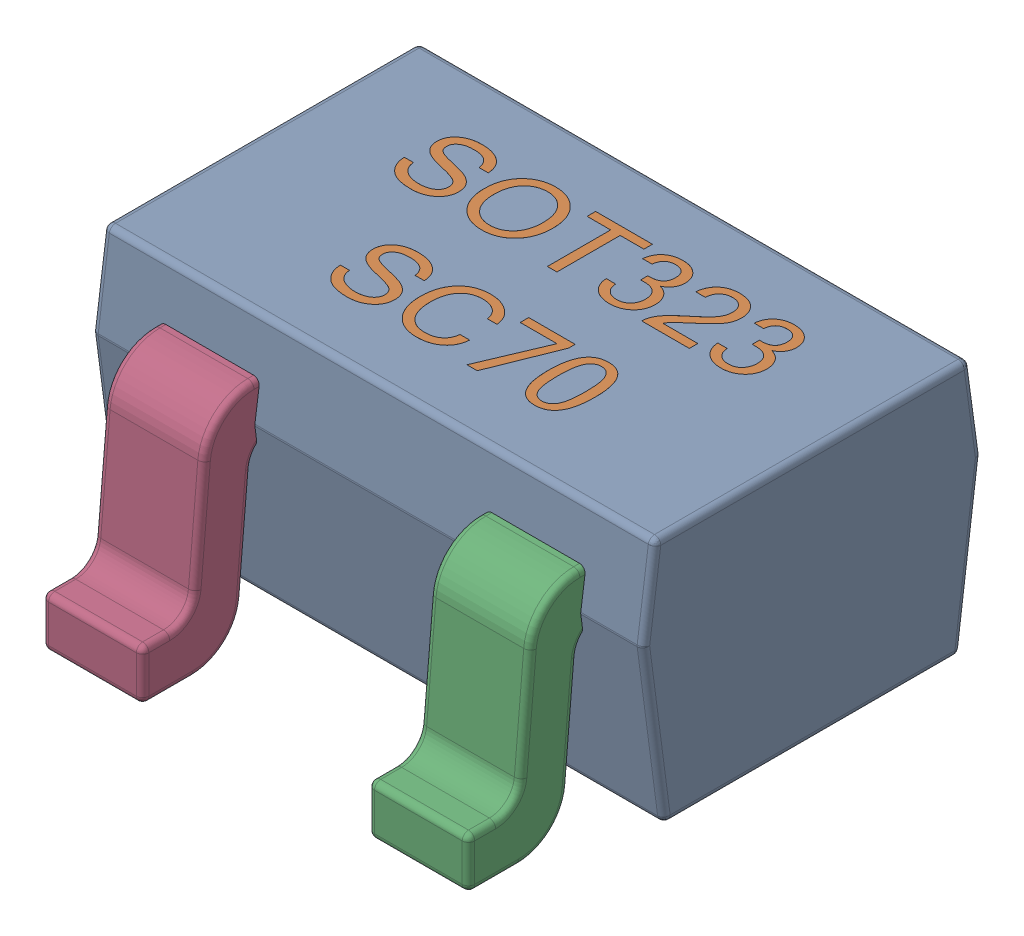
SolidWorks assembly SOT323_(SC70-3)-1.step, configuration Default. Lengths in mm.
Overall size (2.2 1.1 2.25).
5 component instances, 3 part files, 0 mates.
Components (placement in the parent):
- User_Library-SOT323_(SC70-3)-1_K_X_F6rper_1.step-1: User_Library-SOT323_(SC70-3)-1_K_X_F6rper_1.step [Default] x (0 0 -1) z (0 1 0) size (1.35 2.2 1)
- User_Library-SOT323_(SC70-3)-1_Beschriftung_1.step-1: User_Library-SOT323_(SC70-3)-1_Beschriftung_1.step [Default] x (0 0 -1) z (0 1 0) size (0.8 1.45 0.06)
- User_Library-SOT323_(SC70-3)-1_Pins_1.step-1: User_Library-SOT323_(SC70-3)-1_Pins_1.step [Default] at (0.65 0 0) x (0 0 1) z (0 1 0) size (0.6 0.4 0.9)
- User_Library-SOT323_(SC70-3)-1_Pins_1.step-2: User_Library-SOT323_(SC70-3)-1_Pins_1.step [Default] at (-0.65 0 0) x (0 0 1) z (0 1 0) size (0.6 0.4 0.9)
- User_Library-SOT323_(SC70-3)-1_Pins_1.step-3: User_Library-SOT323_(SC70-3)-1_Pins_1.step [Default] x (0 0 -1) z (0 1 0) size (0.6 0.4 0.9)
